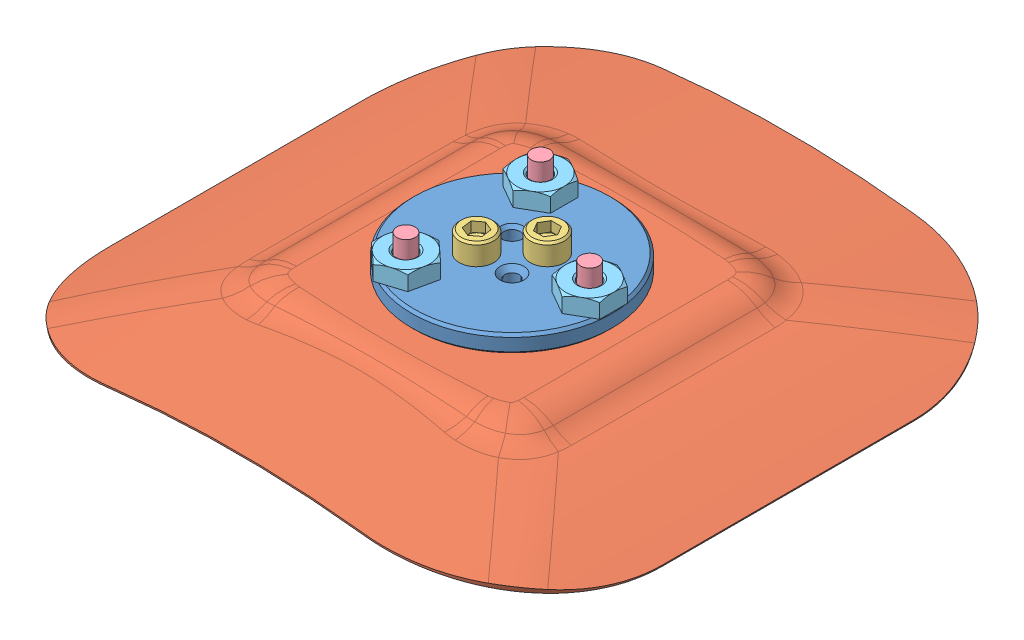
SolidWorks assembly PIT_rail_foot_v2, configuration PIT. Lengths in mm.
Overall size (113.62 41.63 113.59).
13 component instances, 8 part files, 28 mates.
Components (placement in the parent):
- PIT_rail_arm_achor_post_v2-1: PIT_rail_arm_achor_post_v2 [Default] at origin size (40 13.24 40)
- PIT_foot_composit_v6-1: PIT_foot_composit_v6 [Default] at (0 3.7433 0) x (0 -1 0) z (0 0 1) size (12.8 113.62 113.59)
- PIT_rail_hanger_ext_v3-1: PIT_rail_hanger_ext_v3 [Default] at (0 5.7433 -28.8) x (0 -1 0) z (0 0 1) (suppressed, hidden)
- Socket Head Cap Screw_AI-3: Socket Head Cap Screw_AI [HX-SHCS 0.164-32x1x1-N] at (-3.5355 17.4089 3.5355) x (0 -1 0) z (0.991685 0 -0.128686) size (29.57 6.86 6.86)
- Socket Head Cap Screw_AI-4: Socket Head Cap Screw_AI [HX-SHCS 0.164-32x1x1-N] at (3.5355 17.4089 -3.5355) x (0 -1 0) z (0 0 1) size (29.57 6.86 6.86)
- HI-TIGUE-HLT452-5-3-1: HI-TIGUE-HLT452-5-3 [Default] at (15.5 6.9433 0) x (-0.837169 0 -0.546944) z (-0.546944 0 0.837169) size (7.98 14.34 7.98)
- HI-TIGUE-HLT452-5-3-2: HI-TIGUE-HLT452-5-3 [Default] at (-7.75 6.9433 13.4234) x (-0.837169 0 -0.546944) z (-0.546944 0 0.837169) size (7.98 14.34 7.98)
- HI-TIGUE-HLT452-5-3-3: HI-TIGUE-HLT452-5-3 [Default] at (-7.75 6.9433 -13.4234) x (-0.837169 0 -0.546944) z (-0.546944 0 0.837169) size (7.98 14.34 7.98)
- Machine Screw Nut Hex_AI-4: Machine Screw Nut Hex_AI [MSHXNUT 0.190-32-S-N] at (-7.75 16.5453 -13.4234) x (1 0 0) z (0 1 0) size (9.53 11 3.3)
- Machine Screw Nut Hex_AI-5: Machine Screw Nut Hex_AI [MSHXNUT 0.190-32-S-N] at (15.5 16.5453 0) x (1 0 0) z (0 1 0) size (9.53 11 3.3)
- Machine Screw Nut Hex_AI-6: Machine Screw Nut Hex_AI [MSHXNUT 0.190-32-S-N] at (-7.75 16.5453 13.4234) x (0.673341 0 -0.739332) z (0 1 0) size (9.53 11 3.3)
- PIT_rail_hanger_ext_mirror_v3-1: PIT_rail_hanger_ext_mirror_v3 [Default] at (0 5.7433 28.8) x (0 -1 0) z (0 0 1) (suppressed, hidden)
- rail_mount_dowel_pin-1: rail_mount_dowel_pin [long] at (-3.5355 -6 -3.5355) size (3.18 32 3.18)
Mates (geometry in assembly coordinates):
- Coincident1: coordinate: point of PIT_rail_arm_achor_post_v2-1; point of assembly
- Concentric1: concentric anti-aligned: cylinder of PIT_rail_arm_achor_post_v2-1 through (15.5 13.2433 0) axis (0 1 0) radius 2.4574; cylinder of PIT_foot_composit_v6-1 through (15.5 6.9433 0) axis (0 -1 0) radius 1.9844
- Concentric2: concentric anti-aligned: cylinder of PIT_rail_arm_achor_post_v2-1 through (-7.75 13.2433 -13.4234) axis (0 1 0) radius 2.4574; cylinder of PIT_foot_composit_v6-1 through (-7.75 6.9433 -13.4234) axis (0 -1 0) radius 1.9844
- Coincident3: coincident anti-aligned: plane of PIT_rail_arm_achor_post_v2-1 through (0 9.7433 -20) normal (0 -1 0); plane of PIT_foot_composit_v6-1 through (-32.5 9.7433 -32.5) normal (0 1 0)
- Concentric8: concentric aligned: cylinder of PIT_rail_arm_achor_post_v2-1 through (3.5355 13.2433 -3.5355) axis (0 1 0) radius 2.4574; cylinder of Socket Head Cap Screw_AI-4 through (3.5355 49.1589 -3.5355) axis (0 1 0) radius 2.0828
- Coincident6: coincident anti-aligned: plane of PIT_rail_arm_achor_post_v2-1 through (0 13.2433 0) normal (0 1 0); plane of Socket Head Cap Screw_AI-4 through (6.9645 13.2433 -3.5355) normal (0 -1 0)
- Concentric9: concentric aligned: cylinder of Socket Head Cap Screw_AI-3 through (-3.5355 49.1589 3.5355) axis (0 1 0) radius 2.0828; cylinder of PIT_rail_arm_achor_post_v2-1 through (-3.5355 13.2433 3.5355) axis (0 1 0) radius 2.4574
- Coincident7: coincident anti-aligned: plane of PIT_rail_arm_achor_post_v2-1 through (0 13.2433 0) normal (0 1 0); plane of Socket Head Cap Screw_AI-3 through (-3.9768 13.2433 0.135) normal (0 -1 0)
- Concentric10: concentric anti-aligned: cylinder of HI-TIGUE-HLT452-5-3-1 through (15.5 -9.6502 0) axis (0 1 0) radius 2.0726; cylinder of PIT_foot_composit_v6-1 through (15.5 6.9433 0) axis (0 -1 0) radius 1.9844
- Coincident8: coincident anti-aligned: plane of PIT_foot_composit_v6-1 through (-98.7505 6.9433 -25.3402) normal (0 -1 0); plane of HI-TIGUE-HLT452-5-3-1 through (15.4626 6.9433 -0.0244) normal (0 1 0)
- Concentric11: concentric anti-aligned: cylinder of HI-TIGUE-HLT452-5-3-3 through (-7.75 -9.6502 -13.4234) axis (0 1 0) radius 2.0726; cylinder of PIT_foot_composit_v6-1 through (-7.75 6.9433 -13.4234) axis (0 -1 0) radius 1.9844
- Coincident9: coincident anti-aligned: plane of PIT_foot_composit_v6-1 through (-98.7505 6.9433 -25.3402) normal (0 -1 0); plane of HI-TIGUE-HLT452-5-3-3 through (-7.7874 6.9433 -13.4478) normal (0 1 0)
- Concentric12: concentric anti-aligned: cylinder of HI-TIGUE-HLT452-5-3-2 through (-7.75 -9.6502 13.4234) axis (0 1 0) radius 2.0726; cylinder of PIT_foot_composit_v6-1 through (-7.75 6.9433 13.4234) axis (0 -1 0) radius 1.9844
- Coincident10: coincident anti-aligned: plane of PIT_foot_composit_v6-1 through (-98.7505 6.9433 -25.3402) normal (0 -1 0); plane of HI-TIGUE-HLT452-5-3-2 through (-7.7874 6.9433 13.399) normal (0 1 0)
- Concentric13: concentric aligned: cylinder of HI-TIGUE-HLT452-5-3-2 through (-7.75 -9.6502 13.4234) axis (0 1 0) radius 1.8288; cylinder of Machine Screw Nut Hex_AI-6 through (-7.75 13.2433 13.4234) axis (0 1 0) radius 2.0193
- Coincident11: coincident anti-aligned: plane of PIT_rail_arm_achor_post_v2-1 through (0 13.2433 0) normal (0 1 0); plane of Machine Screw Nut Hex_AI-6 through (-11.8158 13.2433 9.7205) normal (0 -1 0)
- Concentric14: concentric aligned: cylinder of Machine Screw Nut Hex_AI-4 through (-7.75 13.2433 -13.4234) axis (0 1 0) radius 2.0193; cylinder of HI-TIGUE-HLT452-5-3-3 through (-7.75 -9.6502 -13.4234) axis (0 1 0) radius 1.8288
- Coincident12: coincident anti-aligned: plane of PIT_rail_arm_achor_post_v2-1 through (0 13.2433 0) normal (0 1 0); plane of Machine Screw Nut Hex_AI-4 through (-7.75 13.2433 -18.9227) normal (0 -1 0)
- Concentric15: concentric aligned: cylinder of Machine Screw Nut Hex_AI-5 through (15.5 13.2433 0) axis (0 1 0) radius 2.0193; cylinder of HI-TIGUE-HLT452-5-3-1 through (15.5 -9.6502 0) axis (0 1 0) radius 1.8288
- Coincident13: coincident anti-aligned: plane of PIT_rail_arm_achor_post_v2-1 through (0 13.2433 0) normal (0 1 0); plane of Machine Screw Nut Hex_AI-5 through (15.5 13.2433 -5.4993) normal (0 -1 0)
- Coincident14: coincident anti-aligned: plane of PIT_rail_arm_achor_post_v2-1 through (0 9.7433 -20) normal (0 -1 0); plane of PIT_rail_hanger_ext_v3-1 through (22 9.7433 -28.8) normal (0 1 0)
- Concentric17: concentric aligned: cylinder of PIT_rail_arm_achor_post_v2-1 through (0 0 0) axis (0 1 0) radius 10; cylinder of PIT_rail_hanger_ext_v3-1 through (0 5.7433 0) axis (0 1 0) radius 10.2
- Concentric18: concentric aligned: cylinder of PIT_rail_arm_achor_post_v2-1 through (15.5 13.2433 0) axis (0 1 0) radius 2.4574; cylinder of PIT_rail_hanger_ext_v3-1 through (15.5 9.7433 0) axis (0 1 0) radius 1.7272
- Coincident15: coincident: plane of PIT_rail_arm_achor_post_v2-1 through (0 9.7433 -20) normal (0 -1 0); plane of PIT_rail_hanger_ext_mirror_v3-1 through (22 9.7433 28.8) normal (0 1 0)
- Concentric20: concentric: cylinder of PIT_rail_arm_achor_post_v2-1 through (0 0 0) axis (0 1 0) radius 10; cylinder of PIT_rail_hanger_ext_mirror_v3-1 through (0 5.7433 0) axis (0 1 0) radius 10.2
- Concentric21: concentric aligned: cylinder of PIT_rail_arm_achor_post_v2-1 through (15.5 13.2433 0) axis (0 1 0) radius 2.4574; cylinder of PIT_rail_hanger_ext_mirror_v3-1 through (15.5 9.7433 0) axis (0 1 0) radius 1.7272
- Distance2: distance = 10 mm anti-aligned: plane of rail_mount_dowel_pin-1 through (-3.5355 10 -3.5355) normal (0 1 0); plane of PIT_rail_arm_achor_post_v2-1 through (0 0 -10) normal (0 -1 0)
- Concentric22: concentric anti-aligned: cylinder of PIT_rail_arm_achor_post_v2-1 through (-3.5355 13.2433 -3.5355) axis (0 1 0) radius 1.5875; cylinder of rail_mount_dowel_pin-1 through (-3.5355 10 -3.5355) axis (0 -1 0) radius 1.5888
